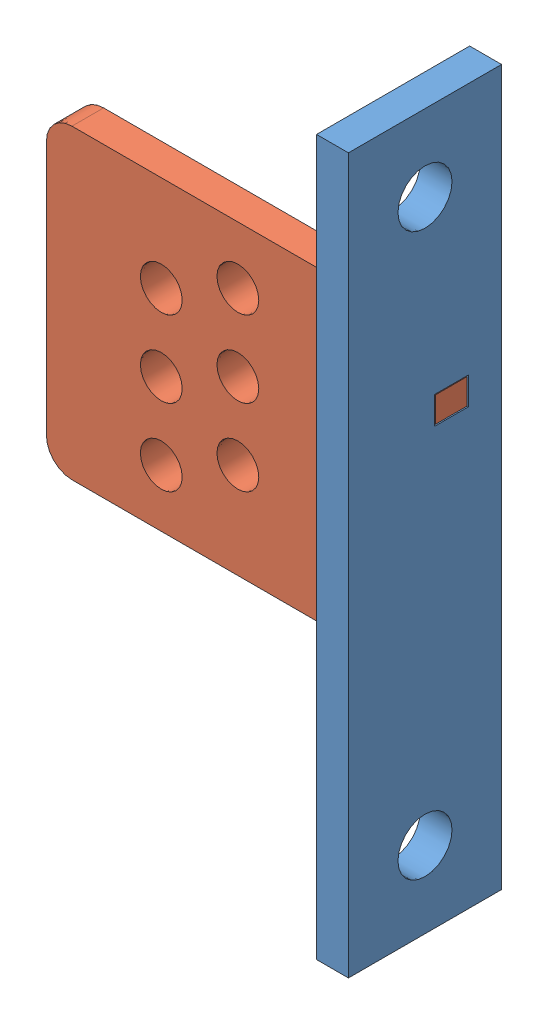
SolidWorks assembly 2812-CC4, configuration 2812-CC4-001. Lengths in mm.
Overall size (96.84 177.8 38.1).
3 component instances, 2 part files, 12 mates.
Components (placement in the parent):
- 2812-CC4 DTL1-1: 2812-CC4 DTL1 [Default] at origin size (7.94 177.8 38.1)
- 2812-CC4 DTL2-1: 2812-CC4 DTL2 [Default] at (3.9688 38.5572 -10.5232) x (0 0 1) z (1 0 0) size (7.87 76.2 96.77) (suppressed, hidden)
- 2812-CC4 DTL2-2: 2812-CC4 DTL2 [Default] at (-3.9688 38.5572 -2.6492) x (0 0 -1) z (-1 0 0) size (7.87 76.2 96.77)
Mates (geometry in assembly coordinates):
- Coincident1: coincident anti-aligned: plane of 2812-CC4 DTL1-1 through (3.9688 -88.9 19.05) normal (1 0 0); plane of 2812-CC4 DTL2-1 through (3.9688 38.5572 -10.5232) normal (-1 0 0)
- Distance2: distance = 2.6492 mm aligned: unknown of 2812-CC4 DTL2-1
- Distance3: distance = 38.5572 mm aligned: unknown of 2812-CC4 DTL2-1
- Coincident2: coincident anti-aligned: plane of 2812-CC4 DTL2-2 through (-3.9688 38.5572 -2.6492) normal (1 0 0); plane of 2812-CC4 DTL1-1 through (-3.9688 -88.9 19.05) normal (-1 0 0)
- Coincident4: coincident aligned: plane of 2812-CC4 DTL2-1 through (92.8688 38.5572 -10.5232) normal (0 1 0); plane of 2812-CC4 DTL2-2 through (-92.8688 38.5572 -2.6492) normal (0 1 0)
- Distance4: distance = 8.5268 mm aligned: plane of 2812-CC4 DTL1-1 through (3.9688 88.9 -19.05) normal (0 0 -1); plane of ? through (-92.8688 -37.6428 -10.5232) normal (0 0 -1)
- Distance5: distance = 50.3428 mm aligned: plane of 2812-CC4 DTL1-1 through (-3.9688 88.9 19.05) normal (0 1 0); plane of ? through (-92.8688 38.5572 -2.6492) normal (0 1 0)
- Coincident5: coincident: plane of 2812-CC4 DTL2-1 through (92.8688 -37.6428 -10.5232) normal (0 0 -1); plane of ? through (-92.8688 -37.6428 -3.8285) normal (0 0 -1)
- Coincident6: coincident aligned: unknown of 2812-CC4 DTL1-1
- Coincident7: coincident aligned: unknown of 2812-CC4 DTL1-1
- Coincident8: coincident aligned: unknown of 2812-CC4 DTL1-1
- Sketch2: unknown = 0.254 mm: unknown of 2812-CC4 DTL2-1; unknown of 2812-CC4 DTL1-1; unknown of 2812-CC4 DTL2-1
